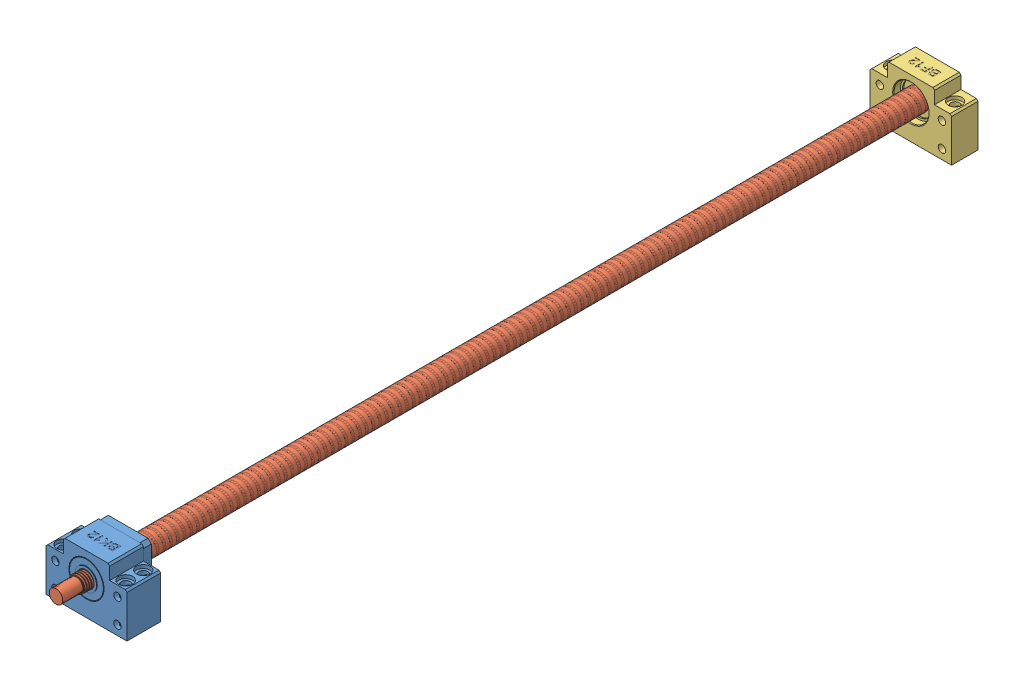
SolidWorks assembly Y_Ballscrew__rev6, configuration Default. Lengths in mm.
Overall size (60.3 43 653.3).
3 component instances, 3 part files, 8 mates.
Components (placement in the parent):
- BK12__rev6-1: BK12__rev6 [Default] at (0 25 0) x (0 0 -1) z (0 1 0) size (31.9 60 43)
- SFU1605-X__rev6-1: SFU1605-X__rev6 [Default] at (0 25 22.6) x (0.939298 -0.343104 0) z (0.343104 0.939298 0) size (18.62 650 16.12)
- BF12__rev6-1: BF12__rev6 [Default] at (0 25 -611.1) x (0 0 -1) z (0 1 0) size (19.6 60.3 43)
Mates (geometry in assembly coordinates):
- Coincident1: coincident anti-aligned: plane of BK12-1 through (30 0 0) normal (0 -1 0)
- Coincident2: coincident anti-aligned: plane of BK12-1 through (0 25 0) normal (-1 0 0)
- Coincident3: coincident anti-aligned: plane of BK12-1 through (0 25 0) normal (0 0 -1)
- Concentric1: concentric anti-aligned: cylinder of BK12-1 through (0 25 -31.4) axis (0 0 1) radius 6.125; cylinder of SFU1605-X__rev6-1 through (0 25 -6.4) axis (0 0 -1) radius 6
- Coincident4: coincident aligned: plane of BK12-1 through (0 25 -31.4) normal (0 0 -1); circle of SFU1605-X-1
- Concentric2: concentric anti-aligned: cylinder of SFU1605-X__rev6-1 through (0 25 -616.4) axis (0 0 -1) radius 5; cylinder of BF12-1 through (0 25 -623.4) axis (0 0 1) radius 5
- Coincident5: coincident aligned: plane of BK12-1 through (30 0 0) normal (0 -1 0); plane of BF12-1 through (30.15 0 -611.1) normal (0 -1 0)
- Coincident6: coincident anti-aligned: plane of SFU1605-X__rev6-1 through (0 25 -616.4) normal (0 0 -1); plane of BF12-1 through (0 25 -616.4) normal (0 0 1)
